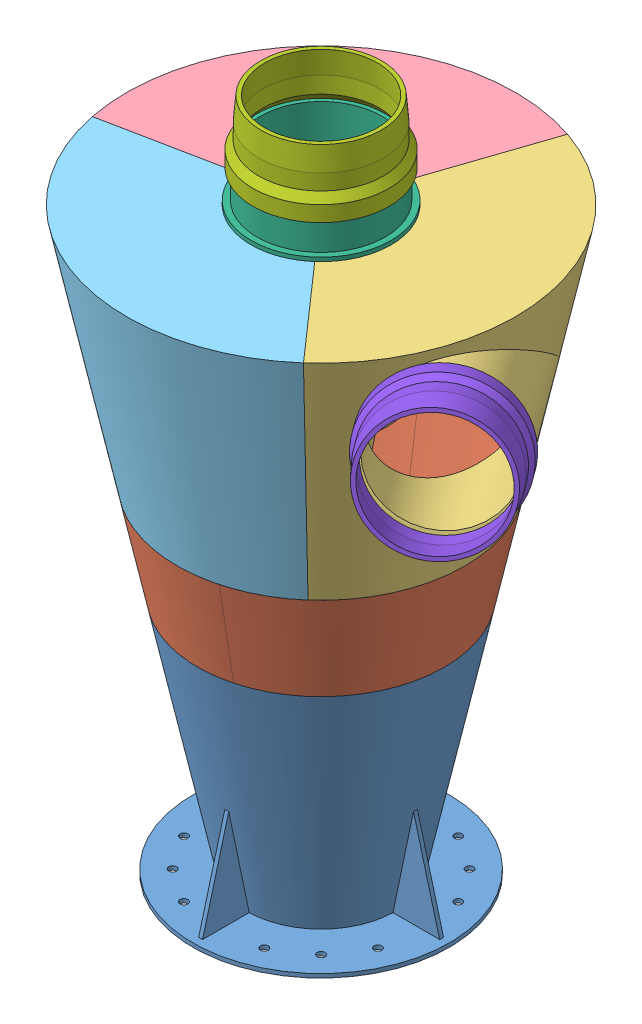
SolidWorks assembly Assembly, configuration Default. Lengths in mm.
Overall size (461.76 550.33 414.12).
9 component instances, 8 part files, 17 mates.
Components (placement in the parent):
- Cyclone seperator bottom-1: Cyclone seperator bottom [Full] at origin size (209.55 196.85 209.55)
- Cyclone seperator middle-1: Cyclone seperator middle [Full] x (-0.25817 0 -0.9661) z (0.9661 0 -0.25817) size (235.57 92.67 117.78)
- Cyclone seperator middle-2: Cyclone seperator middle [Full] x (0.25817 0 0.9661) z (-0.9661 0 0.25817) size (235.57 92.67 117.78)
- Cyclone seperator top 1-1: Cyclone seperator top 1 [Full] x (0.782512 0 -0.622636) z (0.622636 0 0.782512) size (156.26 201.44 260.02)
- Cyclone seperator top 2-1: Cyclone seperator top 2 [Full] x (0.865402 0 -0.501078) z (0.501078 0 0.865402) size (269.68 196.85 142.42)
- Cyclone seperator top 3-1: Cyclone seperator top 3 [Full] x (0.865402 0 -0.501078) z (0.501078 0 0.865402) size (189.72 196.85 209.78)
- top exhaust-1: top exhaust [Default] at (0 469.9 0) x (0.835408 0 -0.549631) z (0.549631 0 0.835408) size (114.3 47.62 114.3)
- Taper fitting-1: Taper fitting [Default] at (0 547.1583 0) x (0.994787 0 -0.101975) z (0 -1 0) size (111.12 111.12 50.8)
- Taper fitting Intake-1: Taper fitting Intake [Default] at (196.5811 421.9468 103.5536) x (0.732017 -0.491594 -0.471684) z (-0.613176 -0.173648 -0.770624) size (107.95 107.95 50.8)
Mates (geometry in assembly coordinates):
- Coincident2: coincident aligned: plane of Cyclone seperator bottom-1 through (0 0 0) normal (0 0 1)
- Coincident3: coincident aligned: plane of Cyclone seperator bottom-1 through (0 0 0) normal (0 1 0)
- Coincident4: coincident aligned: plane of Cyclone seperator bottom-1 through (0 0 0) normal (1 0 0)
- Coincident5: coincident aligned: cone of Cyclone seperator bottom-1 through (0 0 0) axis (0 -1 0); cone of Cyclone seperator middle-2 through (0 0 0) axis (0 -1 0)
- Coincident6: coincident aligned: cone of Cyclone seperator bottom-1 through (0 0 0) axis (0 -1 0); cone of Cyclone seperator middle-1 through (0 0 0) axis (0 -1 0)
- Coincident7: coincident anti-aligned: plane of Cyclone seperator middle-1 through (0 0 0) normal (-0.9661 0 0.25817); plane of Cyclone seperator middle-2 through (0 0 0) normal (0.9661 0 -0.25817)
- Coincident8: coincident aligned: line of Cyclone seperator top 1-1 through (50.8413 469.9 -150.3886) axis (-0.065657 -0.97876 0.194213); line of Cyclone seperator top 2-1 through (50.8413 469.9 -150.3886) axis (-0.065657 -0.97876 0.194213)
- Coincident9: coincident aligned: line of Cyclone seperator top 1-1 through (104.8197 469.9 119.2241) axis (-0.135365 -0.97876 -0.153967); line of Cyclone seperator top 3-1 through (104.8197 469.9 119.2241) axis (-0.135365 -0.97876 -0.153967)
- Coincident10: coincident aligned: plane of Cyclone seperator top 2-1 through (-137.3826 469.9 79.5462) normal (0 1 0); plane of Cyclone seperator top 3-1 through (-137.3826 469.9 79.5462) normal (0 1 0)
- Coincident11: coincident aligned: plane of Cyclone seperator top 1-1 through (-124.2238 469.9 98.8434) normal (0 1 0); plane of Cyclone seperator top 2-1 through (-137.3826 469.9 79.5462) normal (0 1 0)
- Coincident12: coincident aligned: cone of Cyclone seperator middle-1 through (0 0 0) axis (0 -1 0); cone of Cyclone seperator top 1-1 through (0 0 0) axis (0 -1 0)
- Concentric1: concentric anti-aligned: cylinder of Cyclone seperator top 3-1 through (0 0 0) axis (0 -1 0) radius 50.8; cylinder of top exhaust-1 through (0 460.375 0) axis (0 1 0) radius 50.8
- Coincident13: coincident anti-aligned: plane of Cyclone seperator top 1-1 through (-124.2238 469.9 98.8434) normal (0 1 0); plane of top exhaust-1 through (0 469.9 0) normal (0 -1 0)
- Concentric2: concentric aligned: cylinder of Cyclone seperator top 1-1 through (-67.3918 347.1911 -228.2006) axis (0.613176 0.173648 0.770624) radius 50.8; cylinder of Taper fitting Intake-1 through (196.5811 421.9468 103.5536) axis (0.613176 0.173648 0.770624) radius 50.8
- Concentric3: concentric anti-aligned: cylinder of top exhaust-1 through (0 508 0) axis (0 -1 0) radius 52.3875; cylinder of Taper fitting-1 through (0 547.1583 0) axis (0 1 0) radius 52.3875
- Coincident15: coincident aligned: plane of top exhaust-1 through (0 508 0) normal (0 1 0); circle of Taper fitting-1
- Coincident17: coincident aligned: circle of Cyclone seperator top 1-1; circle of Taper fitting Intake-1
